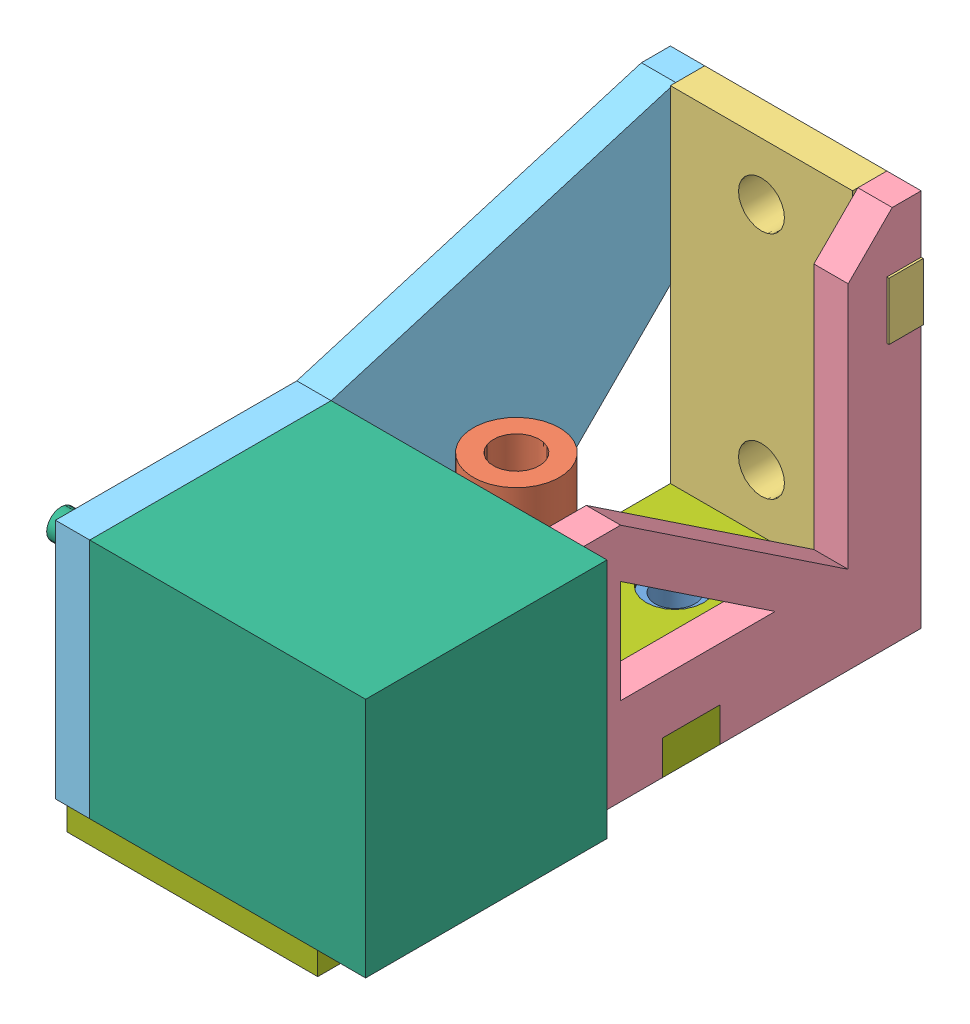
SolidWorks assembly yAssem, configuration Default. Lengths in mm.
Overall size (74 71.28 107).
7 component instances, 7 part files, 42 mates.
Components (placement in the parent):
- brassThing-2: brassThing [Default] at (41.9797 -53.1564 285.6152) x (0.044705 0 0.999) z (-0.999 0 0.044705) size (22.02 10.35 22.02)
- slider-2: slider [Default] at (27.0507 -55.1564 301.5977) x (0.325689 0 0.945477) z (-0.945477 0 0.325689) size (31.7 45.2 20.66)
- xRodHolderFace-2: xRodHolderFace [Default] at (36.6964 -43.8674 264.6052) size (44.4 65.93 5.97)
- yBrace-2: yBrace [Default] at (63.7987 -13.9083 270.5742) x (0 0 1) z (0 -1 0) size (65 5.97 65.93)
- yBraceMotorSide-1: yBraceMotorSide [Default] at (26.1297 -13.9083 270.5742) x (0 0 1) z (0 -1 0) size (107 5.97 65.93)
- motor-1: motor [Default] at (74.1297 -43.8674 329.6052) x (0 0 1) z (0 -1 0) size (42 74 42)
- yMountBaseRight-1: yMountBaseRight [Default] at (26.1297 -49.8364 329.6052) size (42.67 5.97 105)
Mates (geometry in assembly coordinates):
- Coincident1: coincident: plane of ? through (-15.8647 29.5144 87.3935) normal (0 -1 0); plane of ? through (9.4653 29.5144 59.0935) normal (0 1 0)
- Parallel1: parallel: plane of ? through (-15.8647 35.8644 27.3935) normal (0 0 -1); plane of ? through (9.4653 29.5144 27.3935) normal (0 0 -1)
- Coincident3: coincident: plane of ? through (-15.8647 29.5144 87.3935) normal (0 -1 0); plane of ? through (-1.1694 29.5144 70.8474) normal (0 1 0)
- Coincident4: coincident: plane of ? through (-15.8647 35.8644 27.3935) normal (0 0 -1); plane of ? through (9.4653 29.5144 27.3935) normal (0 0 -1)
- Coincident5: coincident: plane of ? through (-15.8647 35.8644 87.3935) normal (0 1 0); plane of ? through (-8.3647 35.8644 87.3935) normal (0 -1 0)
- Coincident6: coincident: plane of ? through (-15.8647 35.8644 87.3935) normal (0 0 1); plane of ? through (-8.3647 35.8644 87.3935) normal (0 0 1)
- Width1: width: plane of ? through (14.1353 35.8644 87.3935) normal (1 0 0); plane of ? through (-15.8647 35.8644 87.3935) normal (-1 0 0); plane of ? through (6.6353 35.8644 87.3935) normal (1 0 0); plane of ? through (-8.3647 35.8644 87.3935) normal (-1 0 0)
- Width2: width: plane of ? through (9.4653 29.5144 59.0935) normal (1 0 0); plane of ? through (-11.1947 29.5144 59.0935) normal (-1 0 0); plane of ? through (-15.8647 35.8644 87.3935) normal (-1 0 0); plane of ? through (14.1353 35.8644 87.3935) normal (1 0 0)
- Concentric1: concentric: cylinder of ? through (-0.0147 35.4834 43.4035) axis (0 -1 0) radius 5.015; cylinder of brassThing-2 through (41.9797 -44.8364 285.6152) axis (0 -1 0) radius 5.015
- Coincident7: coincident: plane of ? through (-15.8647 29.5144 87.3935) normal (0 -1 0); plane of brassThing-2 through (41.9797 -49.8364 285.6152) normal (0 1 0)
- Concentric2: concentric: cylinder of ? through (-0.0147 35.4834 71.0074) axis (0 -1 0) radius 7.5; cylinder of slider-2 through (41.9797 -9.9564 313.2191) axis (0 -1 0) radius 7.5
- Coincident8: coincident: plane of ? through (-15.8647 29.5144 87.3935) normal (0 -1 0); plane of slider-2 through (27.0507 -49.8364 301.5977) normal (0 1 0)
- Coincident9: coincident: plane of ? through (-5.2981 35.4834 22.3935) normal (1 0 0); plane of xRodHolderFace-2 through (36.6964 -49.8364 270.5742) normal (-1 0 0)
- Coincident10: coincident: plane of ? through (5.2686 35.4834 22.3935) normal (0 0 -1); plane of xRodHolderFace-2 through (36.6964 -43.8674 264.6052) normal (0 0 -1)
- Coincident11: coincident: plane of ? through (-15.8647 29.5144 87.3935) normal (0 -1 0); plane of xRodHolderFace-2 through (47.263 -49.8364 270.5742) normal (0 -1 0)
- Coincident13: coincident: plane of xRodHolderFace-2 through (13.8353 85.8234 28.7435) normal (0 1 0); plane of ? through (15.8353 85.8234 28.7435) normal (0 -1 0)
- Coincident14: coincident: plane of ? through (15.8353 35.8644 87.3935) normal (1 0 0); plane of ? through (15.8353 65.8234 28.7435) normal (-1 0 0)
- Coincident15: coincident anti-aligned: plane of xRodHolderFace-2 through (36.6964 -43.8674 270.5742) normal (0 0 1); plane of ? through (15.8353 75.8234 28.7435) normal (0 0 -1)
- Coincident16: coincident: plane of ? through (-15.8647 35.4834 87.3935) normal (0 1 0); plane of yBrace-2 through (57.8297 -43.8674 329.6052) normal (0 -1 0)
- Coincident17: coincident: plane of ? through (15.8353 35.4834 87.3935) normal (1 0 0); plane of yBrace-2 through (57.8297 -13.9083 270.5742) normal (-1 0 0)
- Coincident18: coincident anti-aligned: plane of xRodHolderFace-2 through (36.6964 -43.8674 270.5742) normal (0 0 1); plane of yBrace-2 through (57.8297 -3.9083 270.5742) normal (0 0 -1)
- Coincident19: coincident: plane of ? through (-15.8647 35.4834 87.3935) normal (-1 0 0); plane of slider-2 through (27.0507 -49.8364 301.5977) normal (-0.325689 0 -0.945477)
- Coincident20: coincident: plane of ? through (-15.8647 35.8644 87.3935) normal (0 1 0); plane of ? through (-22.2147 35.8644 67.3935) normal (0 -1 0)
- Coincident21: coincident: plane of ? through (-15.8647 35.8644 87.3935) normal (-1 0 0); plane of ? through (-15.8647 65.8234 28.7435) normal (1 0 0)
- Coincident22: coincident anti-aligned: plane of xRodHolderFace-2 through (36.6964 -43.8674 270.5742) normal (0 0 1); plane of ? through (-22.2147 75.8234 28.7435) normal (0 0 -1)
- Coincident23: coincident anti-aligned: plane of xRodHolderFace-2 through (36.6964 -43.8674 270.5742) normal (0 0 1); plane of yBraceMotorSide-1 through (20.1607 -3.9083 270.5742) normal (0 0 -1)
- Coincident24: coincident: plane of ? through (-15.8647 35.4834 87.3935) normal (0 1 0); plane of yBraceMotorSide-1 through (20.1607 -43.8674 329.6052) normal (0 -1 0)
- Coincident25: coincident: plane of ? through (-21.8337 29.5144 67.3935) normal (-1 0 0); plane of yBraceMotorSide-1 through (20.1607 -13.9083 270.5742) normal (-1 0 0)
- Coincident26: coincident aligned: cylinder of yBraceMotorSide-1 through (26.1297 -22.8674 350.6052) axis (-1 0 0) radius 11; circle of motor-1
- Coincident27: coincident aligned: circle of yBraceMotorSide-1; cylinder of motor-1 through (30.6297 -7.3674 366.1052) axis (-1 0 0) radius 1.5
- Coincident28: coincident anti-aligned: plane of yBraceMotorSide-1 through (26.1297 -13.9083 270.5742) normal (1 0 0); plane of motor-1 through (26.1297 -43.8674 329.6052) normal (-1 0 0)
- Concentric3: concentric aligned: cylinder of slider-2 through (41.9797 -9.9564 313.2191) axis (0 -1 0) radius 7.5; cylinder of yMountBaseRight-1 through (41.9797 -43.8674 313.2191) axis (0 -1 0) radius 7.5
- Coincident29: coincident anti-aligned: plane of xRodHolderFace-2 through (36.6964 -43.8674 270.5742) normal (0 0 1); plane of yMountBaseRight-1 through (47.263 -43.8674 270.5742) normal (0 0 -1)
- Concentric4: concentric anti-aligned: cylinder of brassThing-2 through (41.9797 -55.1864 285.6152) axis (0 1 0) radius 3.455; cylinder of yMountBaseRight-1 through (41.9797 -43.8674 285.6152) axis (0 -1 0) radius 5.015
- Coincident30: coincident: line of xRodHolderFace-2 through (36.6964 -49.8364 264.6052) axis (1 0 0); plane of yMountBaseRight-1 through (26.1297 -49.8364 329.6052) normal (0 -1 0)
- Coincident31: coincident anti-aligned: plane of xRodHolderFace-2 through (47.263 -43.8674 270.5742) normal (1 0 0); plane of yMountBaseRight-1 through (47.263 -43.8674 264.6052) normal (-1 0 0)
- Coincident32: coincident anti-aligned: plane of xRodHolderFace-2 through (57.8297 -43.8674 223.7831) normal (1 0 0); plane of yBrace-2 through (57.8297 -13.9083 270.5742) normal (-1 0 0)
- Coincident33: coincident aligned: plane of yBrace-2 through (63.7987 -49.8364 277.3052) normal (0 -1 0); plane of yMountBaseRight-1 through (26.1297 -49.8364 329.6052) normal (0 -1 0)
- Coincident34: coincident anti-aligned: plane of motor-1 through (26.1297 -43.8674 329.6052) normal (0 -1 0); plane of yMountBaseRight-1 through (26.1297 -43.8674 329.6052) normal (0 1 0)
- Coincident35: coincident anti-aligned: plane of brassThing-2 through (41.9797 -49.8364 285.6152) normal (0 1 0); plane of yMountBaseRight-1 through (26.1297 -49.8364 329.6052) normal (0 -1 0)
- Coincident36: coincident anti-aligned: plane of slider-2 through (27.0507 -49.8364 301.5977) normal (0 1 0); plane of yMountBaseRight-1 through (26.1297 -49.8364 329.6052) normal (0 -1 0)
- Coincident37: coincident anti-aligned: plane of yBraceMotorSide-1 through (26.1297 -13.9083 270.5742) normal (1 0 0); plane of yMountBaseRight-1 through (26.1297 -43.8674 329.6052) normal (-1 0 0)
